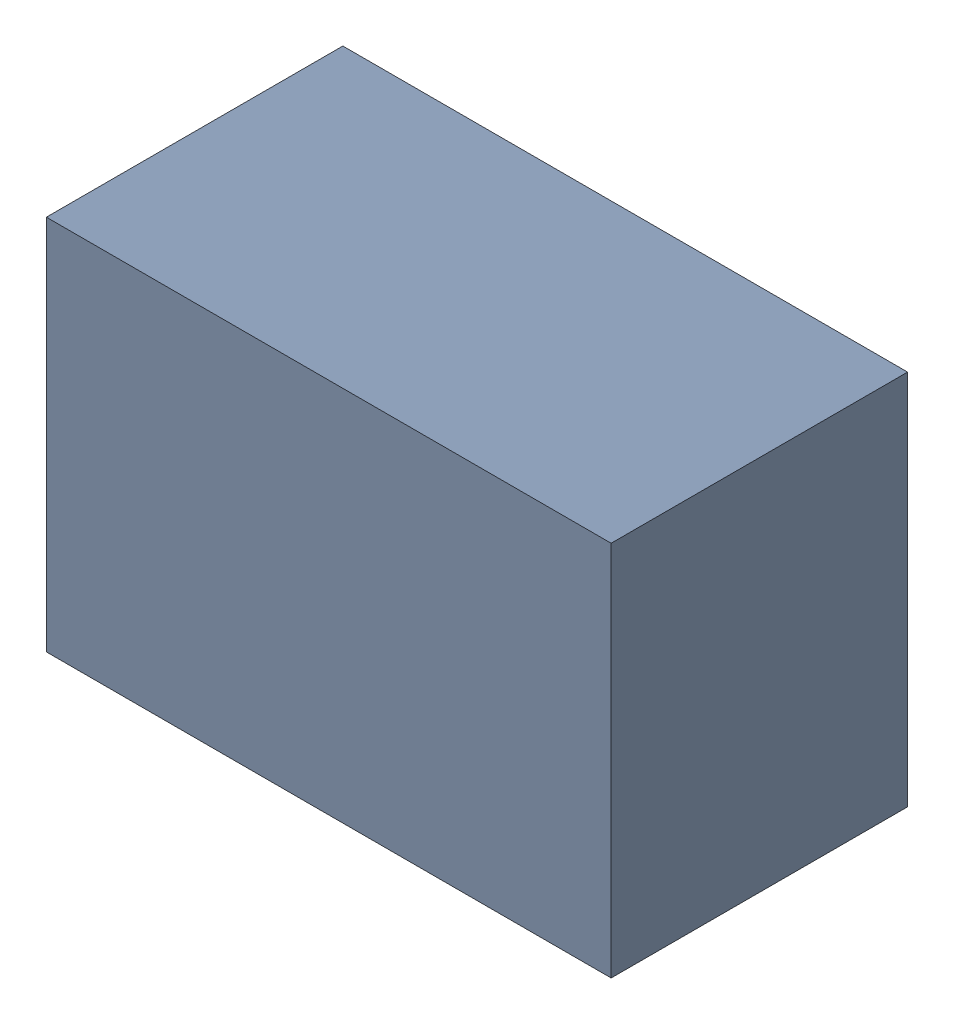
SolidWorks assembly USB67_L1, configuration Default. Lengths in mm.
Overall size (2.29 1.52 1.2).
2 component instances, 1 part files, 0 mates.
Components (placement in the parent):
- 402659088-1: 402659088 [Default] at (147.32 91.821 0) size (2.29 1.52 1.2)
  - Extruded_28-1: Extruded_28 [Default] at origin size (2.29 1.52 1.2)
